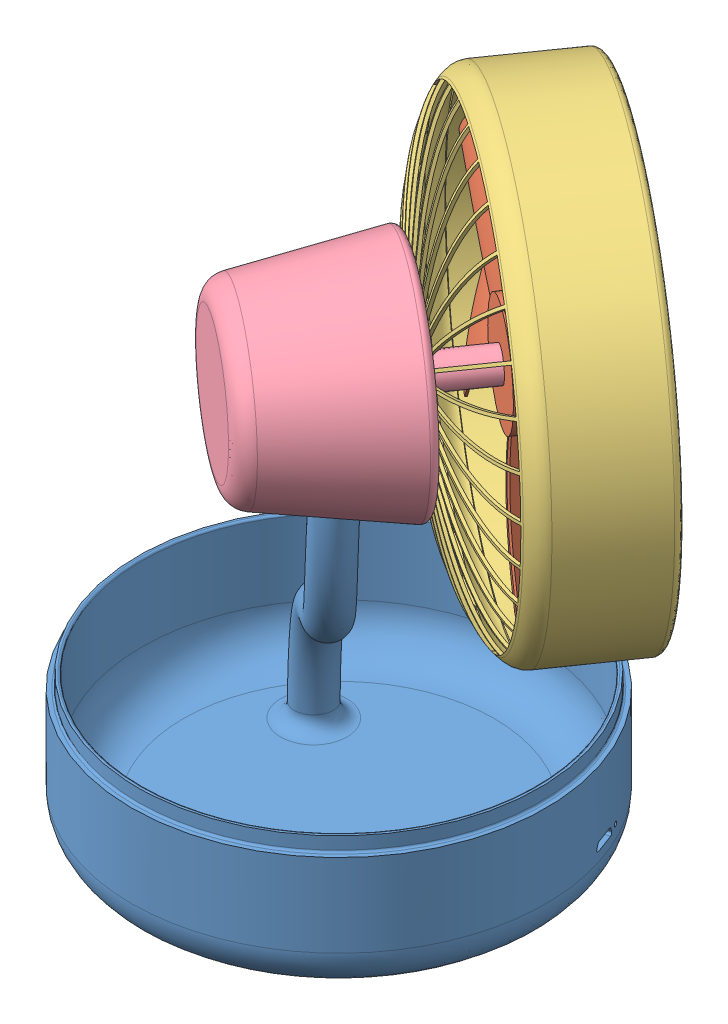
SolidWorks assembly Assem1, configuration Default. Lengths in mm.
Overall size (281.06 334.85 234.96).
5 component instances, 5 part files, 6 mates.
Components (placement in the parent):
- основа2-1: основа2 [Default] at (76.4577 18.6253 155.219) size (200 163.68 200)
- пропеллер-1: пропеллер [Default] at (122.1029 227.3055 138.2271) x (-0.544092 0.748228 -0.37963) z (-0.613625 -0.663442 -0.428146) size (178.45 30.82 178.45)
- сітка -1: сітка  [Default] at (102.3084 227.68 166.4438) x (0.798515 0.227944 0.557149) z (-0.186938 0.973674 -0.130433) size (210 78.6 210)
- мотор-1: мотор [Default] at (71.2339 227.3055 211.1333) x (0 1 0) z (-0.820105 0 -0.572213) size (103.54 115 103.54)
- Part2^Assem1-1: Part2^Assem1 [Default] at origin size (165.15 182.54 126.59) (hidden, virtual)
Mates (geometry in assembly coordinates):
- Concentric1: concentric aligned: circle of основа-1; circle of мотор-1
- Coincident2: coincident anti-aligned: plane of основа-1 through (95.4367 182.3055 176.4455) normal (0 1 0); plane of мотор-1 through (95.4367 182.3055 176.4455) normal (0 -1 0)
- Concentric3: concentric aligned: circle of сітка -1; circle of мотор-1
- Coincident4: coincident aligned: circle of сітка -1; circle of мотор-1
- Concentric4: concentric anti-aligned: circle of пропеллер-1; circle of мотор-1
- Coincident6: coincident anti-aligned: circle of пропеллер-1; circle of мотор-1
